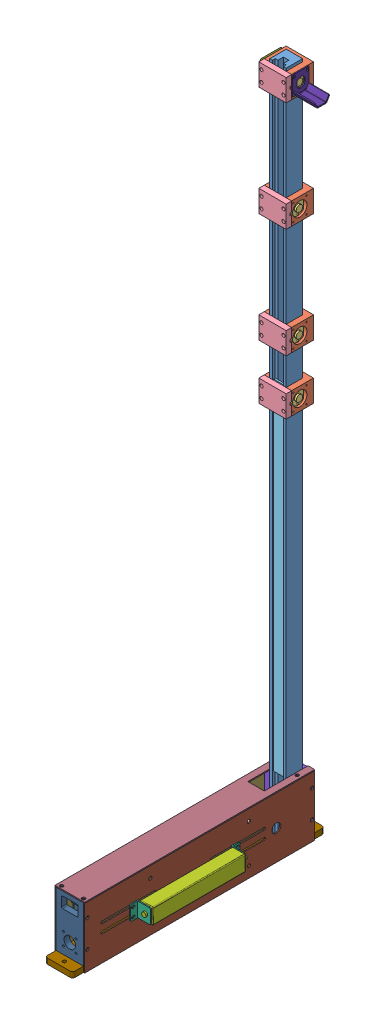
SolidWorks assembly NikeLimboSlide, configuration Default. Lengths in mm.
Overall size (93 1235 460).
37 component instances, 17 part files, 33 mates.
Components (placement in the parent):
- framesquare-1: framesquare [Default] at (-1.0517 0 -0.3078) size (30 1225 30)
- LEDSlideAssem-1: LEDSlideAssem [Default] at (-0.6071 1180 -3.5977) size (50 40 50)
  - LEDSlide-1: LEDSlide [Default] at (-0.4446 0 -1.7102) size (50 40 40)
  - LED-1: LED [Default] at (18.5554 20 3.2898) x (0 -1 0) z (0 0 1) size (25 5.3 20)
  - LED-2: LED [Default] at (-19.4446 20 3.2898) x (0 1 0) z (0 0 1) size (25 5.3 20)
  - PowerSlide-1: PowerSlide [Default] at (0 -0.8358 0) size (50 40 10)
- LEDSlideAssem-2: LEDSlideAssem [Default] at (-0.6071 680 -3.5977) size (50 40 50)
  - LEDSlide-1: LEDSlide [Default] at (-0.4446 0 -1.7102) size (50 40 40)
  - LED-1: LED [Default] at (18.5554 20 3.2898) x (0 -1 0) z (0 0 1) size (25 5.3 20)
  - LED-2: LED [Default] at (-19.4446 20 3.2898) x (0 1 0) z (0 0 1) size (25 5.3 20)
  - PowerSlide-1: PowerSlide [Default] at (0 -0.8358 0) size (50 40 10)
- LEDSlideAssem-3: LEDSlideAssem [Default] at (-0.6071 780 -3.5977) size (50 40 50)
  - LEDSlide-1: LEDSlide [Default] at (-0.4446 0 -1.7102) size (50 40 40)
  - LED-1: LED [Default] at (18.5554 20 3.2898) x (0 -1 0) z (0 0 1) size (25 5.3 20)
  - LED-2: LED [Default] at (-19.4446 20 3.2898) x (0 1 0) z (0 0 1) size (25 5.3 20)
  - PowerSlide-1: PowerSlide [Default] at (0 -0.8358 0) size (50 40 10)
- LEDSlideAssem-4: LEDSlideAssem [Default] at (-0.6071 980 -3.5977) size (50 40 50)
  - LEDSlide-1: LEDSlide [Default] at (-0.4446 0 -1.7102) size (50 40 40)
  - LED-1: LED [Default] at (18.5554 20 3.2898) x (0 -1 0) z (0 0 1) size (25 5.3 20)
  - LED-2: LED [Default] at (-19.4446 20 3.2898) x (0 1 0) z (0 0 1) size (25 5.3 20)
  - PowerSlide-1: PowerSlide [Default] at (0 -0.8358 0) size (50 40 10)
- InsulationSlide-1: InsulationSlide [Default] at (303.2413 0 62.5034) size (20 620 3)
- AreaSensor-1: AreaSensor [Default] at (30.6483 60.0103 216.9303) x (0 0 -1) z (0 -1 0) size (200 27.3 28.6)
  - AreaSensorBracket-1: AreaSensorBracket [Default] at (-80.7618 7.8 15.7103) x (0 0 1) z (0 -1 0) size (26.6 15 25)
  - AreaSensorBracket-2: AreaSensorBracket [Default] at (89.2382 7.8 15.7103) x (0 0 -1) z (0 -1 0) size (26.6 15 25)
  - AreaSensorBW40-04-2: AreaSensorBW40-04 [Default] at (4.2382 0 15.7103) size (185 22.6 28.6)
- frameMount-1: frameMount [Default] at (-1.0517 0 -5.3078) size (50 100 40)
- limboBase-1: limboBase [Default] at (-13.4051 0 -70) size (50 10 460)
- BoxMount-1: BoxMount [Default] at origin size (50 100 10)
- AreaSensorSlide-1: AreaSensorSlide [Default] at origin size (2 110 420)
- BoxCover-1: BoxCover [Default] at origin size (2 110 420)
- BoxTop-1: BoxTop [Default] at origin size (54 2 420)
- Arduino-1: Arduino [Default] at (-16.0517 70.2 339.7226) x (0 0 -1) z (0 -1 0) size (73.25 15.1 53.6)
  - Arduino-1: Arduino [Default] at origin size (68.8 1.6 53.6)
  - Part11^Arduino-1: Part11^Arduino [Default] at (19.5866 0 7.8826) size (22 13.5 16) (virtual)
- LEDCoverAcryl-1: LEDCoverAcryl [Default] at (0 -0.2617 35.8553) size (3 40 40)
- PoleMount-1: PoleMount [Default] at (0.3579 0.2987 0) size (40 37 30)
Mates (geometry in assembly coordinates):
- Coincident4: coincident anti-aligned: plane of framesquare-1 through (13.9483 1225 -15.3078) normal (0 0 -1); plane of LEDSlideAssem-1/LEDSlide-1 through (-16.0517 1179.999 -15.3078) normal (0 0 1)
- Coincident5: coincident anti-aligned: plane of framesquare-1 through (13.9483 1225 14.6922) normal (1 0 0); plane of LEDSlideAssem-1/LEDSlide-1 through (13.9483 1179.999 14.6922) normal (-1 0 0)
- Coincident6: coincident anti-aligned: plane of framesquare-1 through (-16.0517 1225 14.6922) normal (-1 0 0); plane of LEDSlideAssem-4/LEDSlide-1 through (-16.0517 979.999 14.6922) normal (1 0 0)
- Coincident7: coincident anti-aligned: plane of framesquare-1 through (13.9483 1225 -15.3078) normal (0 0 -1); plane of LEDSlideAssem-4/LEDSlide-1 through (-16.0517 979.999 -15.3078) normal (0 0 1)
- Coincident8: coincident anti-aligned: plane of framesquare-1 through (13.9483 1225 -15.3078) normal (0 0 -1); plane of LEDSlideAssem-3/LEDSlide-1 through (-16.0517 779.999 -15.3078) normal (0 0 1)
- Coincident9: coincident anti-aligned: plane of framesquare-1 through (13.9483 1225 14.6922) normal (1 0 0); plane of LEDSlideAssem-3/LEDSlide-1 through (13.9483 779.999 14.6922) normal (-1 0 0)
- Coincident10: coincident anti-aligned: plane of framesquare-1 through (13.9483 1225 -15.3078) normal (0 0 -1); plane of LEDSlideAssem-2/LEDSlide-1 through (-16.0517 679.999 -15.3078) normal (0 0 1)
- Coincident11: coincident anti-aligned: plane of framesquare-1 through (13.9483 1225 14.6922) normal (1 0 0); plane of LEDSlideAssem-2/LEDSlide-1 through (13.9483 679.999 14.6922) normal (-1 0 0)
- Distance2: distance = 5 mm aligned: plane of framesquare-1 through (-16.0517 1225 -15.3078) normal (0 1 0); plane of LEDSlideAssem-1/LEDSlide-1 through (-26.0517 1220 -25.3078) normal (0 1 0)
- Distance3: distance = 200 mm aligned: plane of LEDSlideAssem-1/LEDSlide-1 through (-26.0517 1220 -25.3078) normal (0 1 0); plane of LEDSlideAssem-4/LEDSlide-1 through (-26.0517 1020 -25.3078) normal (0 1 0)
- Distance4: distance = 200 mm aligned: plane of LEDSlideAssem-4/LEDSlide-1 through (-26.0517 1020 -25.3078) normal (0 1 0); plane of LEDSlideAssem-3/LEDSlide-1 through (-26.0517 820 -25.3078) normal (0 1 0)
- Distance5: distance = 100 mm aligned: plane of LEDSlideAssem-3/LEDSlide-1 through (-26.0517 820 -25.3078) normal (0 1 0); plane of LEDSlideAssem-2/LEDSlide-1 through (-26.0517 720 -25.3078) normal (0 1 0)
- Coincident16: coincident anti-aligned: plane of framesquare-1 through (-11.0517 -0.001 9.6922) normal (0 0 1); plane of InsulationSlide-1 through (8.9483 100 9.6922) normal (0 0 -1)
- Coincident17: coincident anti-aligned: plane of framesquare-1 through (-11.0517 -0.001 14.6922) normal (1 0 0); plane of InsulationSlide-1 through (-11.0517 720 12.6922) normal (-1 0 0)
- Parallel1: parallel aligned: plane of framesquare-1 through (-16.0517 1225 -15.3078) normal (0 1 0); plane of AreaSensor-1/AreaSensorBW40-04-2 through (53.2483 58.6 127.6922) normal (0 1 0)
- Coincident22: coincident anti-aligned: plane of framesquare-1 through (13.9483 1225 -15.3078) normal (0 0 -1); plane of frameMount-1 through (-16.0517 0 -15.3078) normal (0 0 1)
- Coincident23: coincident aligned: plane of framesquare-1 through (-16.0517 0 -15.3078) normal (0 -1 0); plane of frameMount-1 through (23.9483 0 -25.3078) normal (0 -1 0)
- Coincident24: coincident anti-aligned: plane of framesquare-1 through (13.9483 1225 14.6922) normal (1 0 0); plane of frameMount-1 through (13.9483 0 14.6922) normal (-1 0 0)
- Coincident25: coincident anti-aligned: plane of framesquare-1 through (-16.0517 0 -15.3078) normal (0 -1 0); plane of limboBase-1 through (23.9483 0 414.6922) normal (0 1 0)
- Distance17: distance = 20 mm aligned: plane of frameMount-1 through (-26.0517 100 -25.3078) normal (0 0 -1); plane of limboBase-1 through (23.9483 -10 -45.3078) normal (0 0 -1)
- Distance11: distance = 315 mm anti-aligned: plane of AreaSensor-1/AreaSensorBracket-1 through (50.9483 57.6 299.6922) normal (0 0 1); plane of framesquare-1 through (13.9483 1225 -15.3078) normal (0 0 -1)
- Coincident49: coincident aligned: plane of frameMount-1 through (23.9483 100 14.6922) normal (1 0 0); plane of limboBase-1 through (23.9483 -10 -45.3078) normal (1 0 0)
- Coincident50: coincident anti-aligned: plane of AreaSensor-1/AreaSensorBracket-2 through (25.9483 57.6 125.6922) normal (-1 0 0); plane of AreaSensorSlide-1 through (25.9483 -10 394.6922) normal (1 0 0)
- Distance16: distance = 40 mm aligned: plane of AreaSensor-1/AreaSensorBW40-04-2 through (53.2483 30 127.6922) normal (0 -1 0); plane of limboBase-1 through (23.9483 -10 414.6922) normal (0 -1 0)
- Distance19: distance = 10 mm anti-aligned: plane of BoxCover-1 through (-26.0517 -10 394.6922) normal (1 0 0); plane of Arduino-1/Arduino-1 through (-16.0517 97 374.1226) normal (-1 0 0)
- Parallel2: parallel aligned: plane of limboBase-1 through (23.9483 -10 414.6922) normal (0 0 1); plane of Arduino-1/Part11^Arduino-1 through (-0.9517 90 378.5726) normal (0 0 1)
- Distance20: distance = 3 mm aligned: plane of Arduino-1/Arduino-1 through (-14.4517 97 305.3226) normal (0 1 0); plane of BoxCover-1 through (-28.0517 100 394.6922) normal (0 1 0)
- Coincident55: coincident aligned: plane of LEDSlideAssem-2/PowerSlide-1 through (-26.0517 720 24.6922) normal (0 1 0); plane of InsulationSlide-1 through (8.9483 720 12.6922) normal (0 1 0)
- Coincident56: coincident anti-aligned: plane of LEDSlideAssem-1/LEDSlide-1 through (-26.0517 1220 14.6922) normal (-1 0 0); plane of LEDCoverAcryl-1 through (-26.0517 1180 -20.3078) normal (1 0 0)
- Concentric1: concentric aligned: cylinder of LEDSlideAssem-1/LEDSlide-1 through (-26.0517 1215 -12.3078) axis (-1 0 0) radius 1.25; cylinder of LEDCoverAcryl-1 through (-26.0507 1215 -12.3078) axis (-1 0 0) radius 2
- Concentric2: concentric aligned: cylinder of LEDSlideAssem-1/LEDSlide-1 through (-26.0517 1185 11.6922) axis (-1 0 0) radius 1.25; cylinder of LEDCoverAcryl-1 through (-26.0507 1185 11.6922) axis (-1 0 0) radius 2
- Coincident57: coincident aligned: plane of LEDSlideAssem-1/LEDSlide-1 through (-26.0517 1220 -25.3078) normal (0 1 0); plane of PoleMount-1 through (25.9483 1220 -15.3078) normal (0 1 0)
- Coincident58: coincident aligned: plane of framesquare-1 through (13.9483 1225 14.6922) normal (0 0 1); plane of PoleMount-1 through (25.9483 1220 14.6922) normal (0 0 1)
